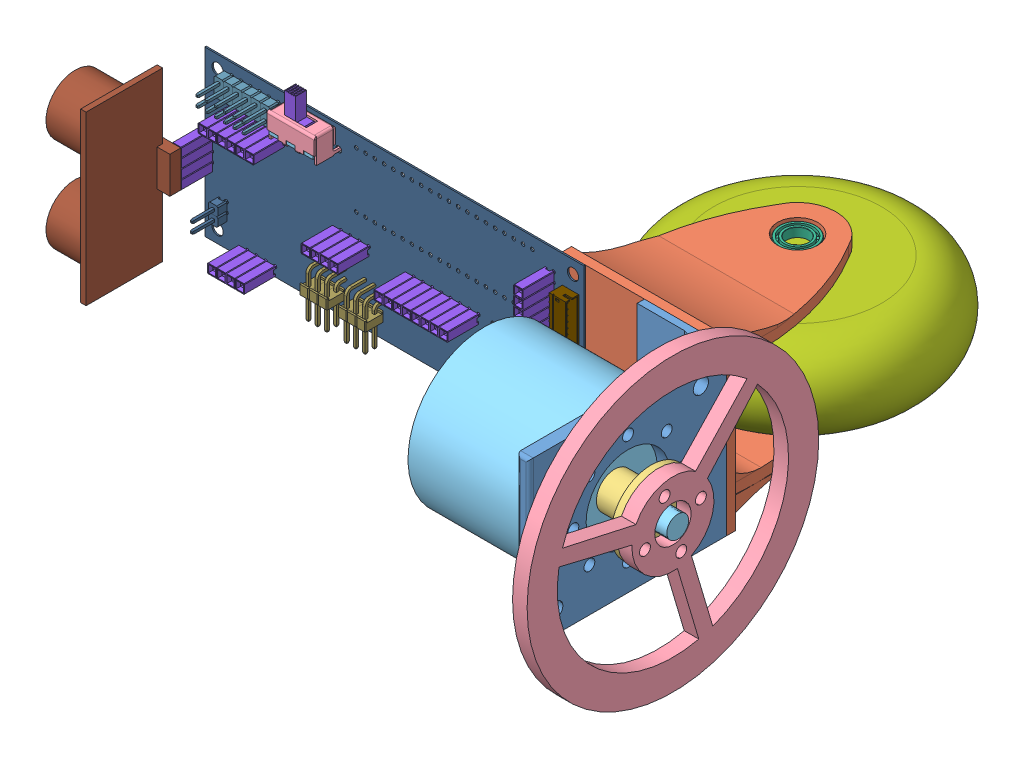
SolidWorks assembly 自行车-装配体_1, configuration Default. Lengths in mm.
Overall size (170.21 99.47 153.76).
186 component instances, 29 part files, 0 mates.
Components (placement in the parent):
- 自行车-装配体-1: 自行车-装配体 [默认] at (98.9927 99.8589 184.7808) size (170.21 99.47 153.76)
  - 自行车-飞轮电机固定件-1: 自行车-飞轮电机固定件 [默认] at (13.6732 19.776 -50.6548) size (22.5 45 54)
  - 自行车-车轮后叉件-1: 自行车-车轮后叉件 [默认] at (36.1732 19.776 -50.6548) x (0 -1 0) z (0 0 -1) size (45 45 52.5)
  - 自行车-6mm联轴器模型-1: 自行车-6mm联轴器模型 [默认] at (44.4868 -2.724 -23.6548) x (0 -0.004012 0.999992) z (-1 0 0) size (22 22 12)
  - 自行车-80mm飞轮模型-1: 自行车-80mm飞轮模型 [默认] at (48.4868 -2.724 -23.6548) x (0 0.958573 0.284848) z (-1 0 0) size (80 80 4)
  - 自行车-飞轮电机模型-1: 自行车-飞轮电机模型 [默认] at (-3.1856 -2.724 -23.6548) x (0 0.181181 -0.98345) z (1 0 0) size (42 42 53)
  - miniature radial ball bearings gb-2: miniature radial ball bearings gb [Rolling bearings FF617-6  GB 7218-1995] at (13.6732 -17.974 -92.6548) x (0 1 0) z (-0.404168 0 0.914685) size (2.5 11.2 11.2)
  - miniature radial ball bearings gb-5: miniature radial ball bearings gb [Rolling bearings FF617-6  GB 7218-1995] at (13.6732 12.526 -92.6548) x (0 -1 0) z (0.445436 0 0.895314) size (2.5 11.2 11.2)
  - 自行车-轮子模型-1: 自行车-轮子模型 [默认] at (0.6732 -2.7471 -92.6468) x (1 0 -0.000617) z (0.000617 0 1) size (70 24 70)
  - balance_bike20211103.step-2: balance_bike20211103.step [默认] at (-167.5194 -100.224 -49.0548) size (104.02 52.12 11.85)
    - Bluetooth.step-1: Bluetooth.step [默认] at origin size (2.54 15.24 11.5)
      - HDR2.54-1P_M.step-1: HDR2.54-1P_M.step [默认] at (156.6926 106.8324 0) x (0 -1 0) z (0 0 1) size (2.54 2.54 11.5)
        - HDR2.54-1P_M-0.step-1: HDR2.54-1P_M-0.step [默认] at origin size (2.54 2.54 11.5)
        - LOGO__.step-1: LOGO__.step [默认] at (0 0.9721 0.0285) x (-1 0 0) z (0 0 -1) size (0.45 0.52 0)
      - HDR2.54-1P_M.step-2: HDR2.54-1P_M.step [默认] at (156.6926 101.7524 0) x (0 -1 0) z (0 0 1) size (2.54 2.54 11.5)
        - HDR2.54-1P_M-0.step-1: HDR2.54-1P_M-0.step [默认] at origin size (2.54 2.54 11.5)
        - LOGO__.step-1: LOGO__.step [默认] at (0 0.9721 0.0285) x (-1 0 0) z (0 0 -1) size (0.45 0.52 0)
      - HDR2.54-1P_M.step-3: HDR2.54-1P_M.step [默认] at (156.6926 104.2924 0) x (0 -1 0) z (0 0 1) size (2.54 2.54 11.5)
        - HDR2.54-1P_M-0.step-1: HDR2.54-1P_M-0.step [默认] at origin size (2.54 2.54 11.5)
        - LOGO__.step-1: LOGO__.step [默认] at (0 0.9721 0.0285) x (-1 0 0) z (0 0 -1) size (0.45 0.52 0)
      - HDR2.54-1P_M.step-4: HDR2.54-1P_M.step [默认] at (156.6926 114.4524 0) x (0 -1 0) z (0 0 1) size (2.54 2.54 11.5)
        - HDR2.54-1P_M-0.step-1: HDR2.54-1P_M-0.step [默认] at origin size (2.54 2.54 11.5)
        - LOGO__.step-1: LOGO__.step [默认] at (0 0.9721 0.0285) x (-1 0 0) z (0 0 -1) size (0.45 0.52 0)
      - HDR2.54-1P_M.step-5: HDR2.54-1P_M.step [默认] at (156.6926 109.3724 0) x (0 -1 0) z (0 0 1) size (2.54 2.54 11.5)
        - HDR2.54-1P_M-0.step-1: HDR2.54-1P_M-0.step [默认] at origin size (2.54 2.54 11.5)
        - LOGO__.step-1: LOGO__.step [默认] at (0 0.9721 0.0285) x (-1 0 0) z (0 0 -1) size (0.45 0.52 0)
      - HDR2.54-1P_M.step-6: HDR2.54-1P_M.step [默认] at (156.6926 111.9124 0) x (0 -1 0) z (0 0 1) size (2.54 2.54 11.5)
        - HDR2.54-1P_M-0.step-1: HDR2.54-1P_M-0.step [默认] at origin size (2.54 2.54 11.5)
        - LOGO__.step-1: LOGO__.step [默认] at (0 0.9721 0.0285) x (-1 0 0) z (0 0 -1) size (0.45 0.52 0)
    - JP1.step-1: JP1.step [默认] at origin size (2.54 5.08 11.5)
      - HDR2.54-1P.step-1: HDR2.54-1P.step [默认] at (67 83.73 0) x (1 0 0) z (0 0 1) size (2.54 2.54 11.5)
        - HDR2.54-1P-1.step-1: HDR2.54-1P-1.step [默认] at origin size (2.54 2.54 11.5)
        - LOGO__-2.step-1: LOGO__-2.step [默认] at (-0.9958 0 0.0285) x (0 -1 0) z (0 0 -1) size (0.45 0.52 0)
      - HDR2.54-1P.step-2: HDR2.54-1P.step [默认] at (67 86.27 0) x (1 0 0) z (0 0 1) size (2.54 2.54 11.5)
        - HDR2.54-1P-1.step-1: HDR2.54-1P-1.step [默认] at origin size (2.54 2.54 11.5)
        - LOGO__-2.step-1: LOGO__-2.step [默认] at (-0.9958 0 0.0285) x (0 -1 0) z (0 0 -1) size (0.45 0.52 0)
    - JP2.step-1: JP2.step [默认] at origin size (7.62 12.85 8.1)
      - HDR-1x2_H.step-1: HDR-1x2_H.step [默认] at (107.4928 86.741 0) size (2.54 12.85 8.1)
        - HDR-1x2_H-3.step-1: HDR-1x2_H-3.step [默认] at origin size (2.54 12.85 8.1)
        - LOGO__-4.step-1: LOGO__-4.step [默认] at (0 -4.7829 0.017) x (-1 0 0) z (0 0 -1) size (0.9 1.04 0.01)
      - HDR-1x2_H.step-2: HDR-1x2_H.step [默认] at (104.9528 86.741 0) size (2.54 12.85 8.1)
        - HDR-1x2_H-3.step-1: HDR-1x2_H-3.step [默认] at origin size (2.54 12.85 8.1)
        - LOGO__-4.step-1: LOGO__-4.step [默认] at (0 -4.7829 0.017) x (-1 0 0) z (0 0 -1) size (0.9 1.04 0.01)
      - HDR-1x2_H.step-3: HDR-1x2_H.step [默认] at (110.0328 86.741 0) size (2.54 12.85 8.1)
        - HDR-1x2_H-3.step-1: HDR-1x2_H-3.step [默认] at origin size (2.54 12.85 8.1)
        - LOGO__-4.step-1: LOGO__-4.step [默认] at (0 -4.7829 0.017) x (-1 0 0) z (0 0 -1) size (0.9 1.04 0.01)
    - JP3.step-1: JP3.step [默认] at origin size (7.62 12.85 8.1)
      - HDR-1x2_H.step-1: HDR-1x2_H.step [默认] at (97.0026 86.741 0) x (1 0 0) z (0 0 1) size (2.54 12.85 8.1)
        - HDR-1x2_H-3.step-1: HDR-1x2_H-3.step [默认] at origin size (2.54 12.85 8.1)
        - LOGO__-4.step-1: LOGO__-4.step [默认] at (0 -4.7829 0.017) x (-1 0 0) z (0 0 -1) size (0.9 1.04 0.01)
      - HDR-1x2_H.step-2: HDR-1x2_H.step [默认] at (94.4626 86.741 0) x (1 0 0) z (0 0 1) size (2.54 12.85 8.1)
        - HDR-1x2_H-3.step-1: HDR-1x2_H-3.step [默认] at origin size (2.54 12.85 8.1)
        - LOGO__-4.step-1: LOGO__-4.step [默认] at (0 -4.7829 0.017) x (-1 0 0) z (0 0 -1) size (0.9 1.04 0.01)
      - HDR-1x2_H.step-3: HDR-1x2_H.step [默认] at (99.5426 86.741 0) x (1 0 0) z (0 0 1) size (2.54 12.85 8.1)
        - HDR-1x2_H-3.step-1: HDR-1x2_H-3.step [默认] at origin size (2.54 12.85 8.1)
        - LOGO__-4.step-1: LOGO__-4.step [默认] at (0 -4.7829 0.017) x (-1 0 0) z (0 0 -1) size (0.9 1.04 0.01)
    - JP4.step-1: JP4.step [默认] at origin size (15.24 5.08 11.5)
      - HDR2.54-1x2P.step-1: HDR2.54-1x2P.step [默认] at (68.5038 116.9416 0) x (1 0 0) z (0 0 1) size (2.54 5.08 11.5)
        - HDR2.54-1x2P-5.step-1: HDR2.54-1x2P-5.step [默认] at origin size (2.54 5.08 11.5)
        - LOGO__-6.step-1: LOGO__-6.step [默认] at (0 -1.2605 0.4975) x (-1 0 0) z (0 0 -1) size (0.75 0.87 0.01)
      - HDR2.54-1x2P.step-2: HDR2.54-1x2P.step [默认] at (76.1238 116.9416 0) x (1 0 0) z (0 0 1) size (2.54 5.08 11.5)
        - HDR2.54-1x2P-5.step-1: HDR2.54-1x2P-5.step [默认] at origin size (2.54 5.08 11.5)
        - LOGO__-6.step-1: LOGO__-6.step [默认] at (0 -1.2605 0.4975) x (-1 0 0) z (0 0 -1) size (0.75 0.87 0.01)
      - HDR2.54-1x2P.step-3: HDR2.54-1x2P.step [默认] at (73.5838 116.9416 0) x (1 0 0) z (0 0 1) size (2.54 5.08 11.5)
        - HDR2.54-1x2P-5.step-1: HDR2.54-1x2P-5.step [默认] at origin size (2.54 5.08 11.5)
        - LOGO__-6.step-1: LOGO__-6.step [默认] at (0 -1.2605 0.4975) x (-1 0 0) z (0 0 -1) size (0.75 0.87 0.01)
      - HDR2.54-1x2P.step-4: HDR2.54-1x2P.step [默认] at (81.2038 116.9416 0) x (1 0 0) z (0 0 1) size (2.54 5.08 11.5)
        - HDR2.54-1x2P-5.step-1: HDR2.54-1x2P-5.step [默认] at origin size (2.54 5.08 11.5)
        - LOGO__-6.step-1: LOGO__-6.step [默认] at (0 -1.2605 0.4975) x (-1 0 0) z (0 0 -1) size (0.75 0.87 0.01)
      - HDR2.54-1x2P.step-5: HDR2.54-1x2P.step [默认] at (78.6638 116.9416 0) x (1 0 0) z (0 0 1) size (2.54 5.08 11.5)
        - HDR2.54-1x2P-5.step-1: HDR2.54-1x2P-5.step [默认] at origin size (2.54 5.08 11.5)
        - LOGO__-6.step-1: LOGO__-6.step [默认] at (0 -1.2605 0.4975) x (-1 0 0) z (0 0 -1) size (0.75 0.87 0.01)
      - HDR2.54-1x2P.step-6: HDR2.54-1x2P.step [默认] at (71.0438 116.9416 0) x (1 0 0) z (0 0 1) size (2.54 5.08 11.5)
        - HDR2.54-1x2P-5.step-1: HDR2.54-1x2P-5.step [默认] at origin size (2.54 5.08 11.5)
        - LOGO__-6.step-1: LOGO__-6.step [默认] at (0 -1.2605 0.4975) x (-1 0 0) z (0 0 -1) size (0.75 0.87 0.01)
    - JP6.step-1: JP6.step [默认] at origin size (5 13.5 6)
      - ZH1.5-WI-8P.step-1: ZH1.5-WI-8P.step [默认] at (160.0708 106.9594 0) x (0 1 0) z (0 0 1) size (13.5 5 6)
        - ZH1.5-WI-____.step-1: ZH1.5-WI-____.step [默认] at (-5.25 0 0.05) size (0.5 4 4.75)
        - ZH1.5-WI-____.step-2: ZH1.5-WI-____.step [默认] at (-3.75 0 0.05) size (0.5 4 4.75)
        - ZH1.5-WI-____.step-3: ZH1.5-WI-____.step [默认] at (-2.25 0 0.05) size (0.5 4 4.75)
        - ZH1.5-WI-____.step-4: ZH1.5-WI-____.step [默认] at (-0.75 0 0.05) size (0.5 4 4.75)
        - LOGO__0.25.step-1: LOGO__0.25.step [默认] at (-0.0154 -2.5616 0.045) size (0.75 0.87 0.01)
        - ZH1.5-WI-____.step-5: ZH1.5-WI-____.step [默认] at (0.75 0 0.05) size (0.5 4 4.75)
        - ZH1.5-WI-____.step-6: ZH1.5-WI-____.step [默认] at (2.25 0 0.05) size (0.5 4 4.75)
        - ZH1.5-WI-____.step-7: ZH1.5-WI-____.step [默认] at (3.75 0 0.05) size (0.5 4 4.75)
        - ZH1.5-WI-____.step-8: ZH1.5-WI-____.step [默认] at (5.25 0 0.05) size (0.5 4 4.75)
        - ZH1.5-WI-8P-7.step-1: ZH1.5-WI-8P-7.step [默认] at origin size (13.5 4.5 3.6)
    - MOTOR1.step-1: MOTOR1.step [默认] at origin size (6.6 5.9 7.4)
      - PH2.0-WI-2P.step-1: PH2.0-WI-2P.step [默认] at (158.7246 86.868 0) x (0 1 0) z (0 0 1) size (5.9 6.6 7.4)
        - PH2.0-WI-2P-8.step-1: PH2.0-WI-2P-8.step [默认] at origin size (5.9 6 4.7)
        - PH2.0-WI-____.step-1: PH2.0-WI-____.step [默认] at (-1 0 0.05) size (0.6 5.5 6)
        - PH2.0-WI-____.step-2: PH2.0-WI-____.step [默认] at (1 0 0.05) size (0.6 5.5 6)
        - LOGO__0.25-9.step-1: LOGO__0.25-9.step [默认] at (-0.0263 -2.2762 0.045) size (0.75 0.87 0.01)
    - MPU6050.step-1: MPU6050.step [默认] at origin size (20.32 2.54 11.5)
      - HDR2.54-1P_M.step-1: HDR2.54-1P_M.step [默认] at (120.8532 94.0308 0) x (1 0 0) z (0 0 1) size (2.54 2.54 11.5)
        - HDR2.54-1P_M-0.step-1: HDR2.54-1P_M-0.step [默认] at origin size (2.54 2.54 11.5)
        - LOGO__.step-1: LOGO__.step [默认] at (0 0.9721 0.0285) x (-1 0 0) z (0 0 -1) size (0.45 0.52 0)
      - HDR2.54-1P_M.step-2: HDR2.54-1P_M.step [默认] at (125.9332 94.0308 0) x (1 0 0) z (0 0 1) size (2.54 2.54 11.5)
        - HDR2.54-1P_M-0.step-1: HDR2.54-1P_M-0.step [默认] at origin size (2.54 2.54 11.5)
        - LOGO__.step-1: LOGO__.step [默认] at (0 0.9721 0.0285) x (-1 0 0) z (0 0 -1) size (0.45 0.52 0)
      - HDR2.54-1P_M.step-3: HDR2.54-1P_M.step [默认] at (128.4732 94.0308 0) x (1 0 0) z (0 0 1) size (2.54 2.54 11.5)
        - HDR2.54-1P_M-0.step-1: HDR2.54-1P_M-0.step [默认] at origin size (2.54 2.54 11.5)
        - LOGO__.step-1: LOGO__.step [默认] at (0 0.9721 0.0285) x (-1 0 0) z (0 0 -1) size (0.45 0.52 0)
      - HDR2.54-1P_M.step-4: HDR2.54-1P_M.step [默认] at (123.3932 94.0308 0) x (1 0 0) z (0 0 1) size (2.54 2.54 11.5)
        - HDR2.54-1P_M-0.step-1: HDR2.54-1P_M-0.step [默认] at origin size (2.54 2.54 11.5)
        - LOGO__.step-1: LOGO__.step [默认] at (0 0.9721 0.0285) x (-1 0 0) z (0 0 -1) size (0.45 0.52 0)
      - HDR2.54-1P_M.step-5: HDR2.54-1P_M.step [默认] at (133.5532 94.0308 0) x (1 0 0) z (0 0 1) size (2.54 2.54 11.5)
        - HDR2.54-1P_M-0.step-1: HDR2.54-1P_M-0.step [默认] at origin size (2.54 2.54 11.5)
        - LOGO__.step-1: LOGO__.step [默认] at (0 0.9721 0.0285) x (-1 0 0) z (0 0 -1) size (0.45 0.52 0)
      - HDR2.54-1P_M.step-6: HDR2.54-1P_M.step [默认] at (136.0932 94.0308 0) x (1 0 0) z (0 0 1) size (2.54 2.54 11.5)
        - HDR2.54-1P_M-0.step-1: HDR2.54-1P_M-0.step [默认] at origin size (2.54 2.54 11.5)
        - LOGO__.step-1: LOGO__.step [默认] at (0 0.9721 0.0285) x (-1 0 0) z (0 0 -1) size (0.45 0.52 0)
      - HDR2.54-1P_M.step-7: HDR2.54-1P_M.step [默认] at (131.0132 94.0308 0) x (1 0 0) z (0 0 1) size (2.54 2.54 11.5)
        - HDR2.54-1P_M-0.step-1: HDR2.54-1P_M-0.step [默认] at origin size (2.54 2.54 11.5)
        - LOGO__.step-1: LOGO__.step [默认] at (0 0.9721 0.0285) x (-1 0 0) z (0 0 -1) size (0.45 0.52 0)
      - HDR2.54-1P_M.step-8: HDR2.54-1P_M.step [默认] at (118.3132 94.0308 0) x (1 0 0) z (0 0 1) size (2.54 2.54 11.5)
        - HDR2.54-1P_M-0.step-1: HDR2.54-1P_M-0.step [默认] at origin size (2.54 2.54 11.5)
        - LOGO__.step-1: LOGO__.step [默认] at (0 0.9721 0.0285) x (-1 0 0) z (0 0 -1) size (0.45 0.52 0)
    - S1.step-1: S1.step [默认] at origin size (13 12.9 9.1)
      - User_Library-SLIDE_SWITCH_SS12F23.step-1: User_Library-SLIDE_SWITCH_SS12F23.step [默认] at (91.2963 119.8635 0.5) x (-1 0 0) z (0 1 0) size (13 9.1 12.9)
        - User_Library-SLIDE_SWITCH_SS12F23_SLIDE_SWITCH_SS12F23_CAPA_Valor_predeterminado.step-1: User_Library-SLIDE_SWITCH_SS12F23_SLIDE_SWITCH_SS12F23_CAPA_Valor_predeterminado.step [默认] at (-0.1668 2.3476 0) size (13 8.18 6.9)
        - User_Library-SLIDE_SWITCH_SS12F23_SLIDE_SWITCH_SS12F23_PCB_Valor_predeterminado.step-1: User_Library-SLIDE_SWITCH_SS12F23_SLIDE_SWITCH_SS12F23_PCB_Valor_predeterminado.step [默认] at (12.2412 -9.4974 -5) size (12 5.5 1)
        - User_Library-SLIDE_SWITCH_SS12F23_SLIDE_SWITCH_SS12F23_CENTRAL_Valor_predeterminado.step-1: User_Library-SLIDE_SWITCH_SS12F23_SLIDE_SWITCH_SS12F23_CENTRAL_Valor_predeterminado.step [默认] at (-1.4168 2.5976 -3) size (2.5 6.45 3.5)
        - User_Library-SLIDE_SWITCH_SS12F23_SLIDE_SWITCH_SS12F23_LATERAL_Valor_predeterminado.step-1: User_Library-SLIDE_SWITCH_SS12F23_SLIDE_SWITCH_SS12F23_LATERAL_Valor_predeterminado.step [默认] at (-4.4168 2.5976 -3) size (2.5 6.45 3)
        - User_Library-SLIDE_SWITCH_SS12F23_SLIDE_SWITCH_SS12F23_LATERAL_Valor_predeterminado.step-2: User_Library-SLIDE_SWITCH_SS12F23_SLIDE_SWITCH_SS12F23_LATERAL_Valor_predeterminado.step [默认] at (1.5832 2.5976 -3) size (2.5 6.45 3)
        - User_Library-SLIDE_SWITCH_SS12F23_SLIDE_SWITCH_SS12F23_ATUADOR_Valor_predeterminado.step-1: User_Library-SLIDE_SWITCH_SS12F23_SLIDE_SWITCH_SS12F23_ATUADOR_Valor_predeterminado.step [默认] at (1.3332 2.3976 -3.25) size (7 4.5 9.75)
        - User_Library-SLIDE_SWITCH_SS12F23_SLIDE_SWITCH_SS12F23_Contato_Valor_predeterminado.step-1: User_Library-SLIDE_SWITCH_SS12F23_SLIDE_SWITCH_SS12F23_Contato_Valor_predeterminado.step [默认] at (3.3332 3.1476 -2.25) x (0 -1 0) z (0 0 -1) size (1.5 5 2)
    - U1.step-1: U1.step [默认] at origin size (15.24 34.54 11.5)
      - HDR2.54-1P_M.step-1: HDR2.54-1P_M.step [默认] at (75.2254 77.5402 0) x (-1 0 0) z (0 0 1) size (2.54 2.54 11.5)
        - HDR2.54-1P_M-0.step-1: HDR2.54-1P_M-0.step [默认] at origin size (2.54 2.54 11.5)
        - LOGO__.step-1: LOGO__.step [默认] at (0 0.9721 0.0285) x (-1 0 0) z (0 0 -1) size (0.45 0.52 0)
      - HDR2.54-1P_M.step-2: HDR2.54-1P_M.step [默认] at (72.6854 77.5402 0) x (-1 0 0) z (0 0 1) size (2.54 2.54 11.5)
        - HDR2.54-1P_M-0.step-1: HDR2.54-1P_M-0.step [默认] at origin size (2.54 2.54 11.5)
        - LOGO__.step-1: LOGO__.step [默认] at (0 0.9721 0.0285) x (-1 0 0) z (0 0 -1) size (0.45 0.52 0)
      - HDR2.54-1P_M.step-3: HDR2.54-1P_M.step [默认] at (80.3054 77.5402 0) x (-1 0 0) z (0 0 1) size (2.54 2.54 11.5)
        - HDR2.54-1P_M-0.step-1: HDR2.54-1P_M-0.step [默认] at origin size (2.54 2.54 11.5)
        - LOGO__.step-1: LOGO__.step [默认] at (0 0.9721 0.0285) x (-1 0 0) z (0 0 -1) size (0.45 0.52 0)
      - HDR2.54-1P_M.step-4: HDR2.54-1P_M.step [默认] at (77.7654 77.5402 0) x (-1 0 0) z (0 0 1) size (2.54 2.54 11.5)
        - HDR2.54-1P_M-0.step-1: HDR2.54-1P_M-0.step [默认] at origin size (2.54 2.54 11.5)
        - LOGO__.step-1: LOGO__.step [默认] at (0 0.9721 0.0285) x (-1 0 0) z (0 0 -1) size (0.45 0.52 0)
      - HDR2.54-1P_M.step-5: HDR2.54-1P_M.step [默认] at (75.2255 109.5403 0) x (-1 0 0) z (0 0 1) size (2.54 2.54 11.5)
        - HDR2.54-1P_M-0.step-1: HDR2.54-1P_M-0.step [默认] at origin size (2.54 2.54 11.5)
        - LOGO__.step-1: LOGO__.step [默认] at (0 0.9721 0.0285) x (-1 0 0) z (0 0 -1) size (0.45 0.52 0)
      - HDR2.54-1P_M.step-6: HDR2.54-1P_M.step [默认] at (70.1455 109.5403 0) x (-1 0 0) z (0 0 1) size (2.54 2.54 11.5)
        - HDR2.54-1P_M-0.step-1: HDR2.54-1P_M-0.step [默认] at origin size (2.54 2.54 11.5)
        - LOGO__.step-1: LOGO__.step [默认] at (0 0.9721 0.0285) x (-1 0 0) z (0 0 -1) size (0.45 0.52 0)
      - HDR2.54-1P_M.step-7: HDR2.54-1P_M.step [默认] at (72.6855 109.5403 0) x (-1 0 0) z (0 0 1) size (2.54 2.54 11.5)
        - HDR2.54-1P_M-0.step-1: HDR2.54-1P_M-0.step [默认] at origin size (2.54 2.54 11.5)
        - LOGO__.step-1: LOGO__.step [默认] at (0 0.9721 0.0285) x (-1 0 0) z (0 0 -1) size (0.45 0.52 0)
      - HDR2.54-1P_M.step-8: HDR2.54-1P_M.step [默认] at (82.8455 109.5403 0) x (-1 0 0) z (0 0 1) size (2.54 2.54 11.5)
        - HDR2.54-1P_M-0.step-1: HDR2.54-1P_M-0.step [默认] at origin size (2.54 2.54 11.5)
        - LOGO__.step-1: LOGO__.step [默认] at (0 0.9721 0.0285) x (-1 0 0) z (0 0 -1) size (0.45 0.52 0)
      - HDR2.54-1P_M.step-9: HDR2.54-1P_M.step [默认] at (77.7655 109.5403 0) x (-1 0 0) z (0 0 1) size (2.54 2.54 11.5)
        - HDR2.54-1P_M-0.step-1: HDR2.54-1P_M-0.step [默认] at origin size (2.54 2.54 11.5)
        - LOGO__.step-1: LOGO__.step [默认] at (0 0.9721 0.0285) x (-1 0 0) z (0 0 -1) size (0.45 0.52 0)
      - HDR2.54-1P_M.step-10: HDR2.54-1P_M.step [默认] at (80.3055 109.5403 0) x (-1 0 0) z (0 0 1) size (2.54 2.54 11.5)
        - HDR2.54-1P_M-0.step-1: HDR2.54-1P_M-0.step [默认] at origin size (2.54 2.54 11.5)
        - LOGO__.step-1: LOGO__.step [默认] at (0 0.9721 0.0285) x (-1 0 0) z (0 0 -1) size (0.45 0.52 0)
    - ultrasonic.step-1: ultrasonic.step [默认] at origin size (2.54 10.16 11.5)
      - HDR2.54-1P_M.step-1: HDR2.54-1P_M.step [默认] at (63 96.23 0) x (0 -1 0) z (0 0 1) size (2.54 2.54 11.5)
        - HDR2.54-1P_M-0.step-1: HDR2.54-1P_M-0.step [默认] at origin size (2.54 2.54 11.5)
        - LOGO__.step-1: LOGO__.step [默认] at (0 0.9721 0.0285) x (-1 0 0) z (0 0 -1) size (0.45 0.52 0)
      - HDR2.54-1P_M.step-2: HDR2.54-1P_M.step [默认] at (63 93.69 0) x (0 -1 0) z (0 0 1) size (2.54 2.54 11.5)
        - HDR2.54-1P_M-0.step-1: HDR2.54-1P_M-0.step [默认] at origin size (2.54 2.54 11.5)
        - LOGO__.step-1: LOGO__.step [默认] at (0 0.9721 0.0285) x (-1 0 0) z (0 0 -1) size (0.45 0.52 0)
      - HDR2.54-1P_M.step-3: HDR2.54-1P_M.step [默认] at (63 101.31 0) x (0 -1 0) z (0 0 1) size (2.54 2.54 11.5)
        - HDR2.54-1P_M-0.step-1: HDR2.54-1P_M-0.step [默认] at origin size (2.54 2.54 11.5)
        - LOGO__.step-1: LOGO__.step [默认] at (0 0.9721 0.0285) x (-1 0 0) z (0 0 -1) size (0.45 0.52 0)
      - HDR2.54-1P_M.step-4: HDR2.54-1P_M.step [默认] at (63 98.77 0) x (0 -1 0) z (0 0 1) size (2.54 2.54 11.5)
        - HDR2.54-1P_M-0.step-1: HDR2.54-1P_M-0.step [默认] at origin size (2.54 2.54 11.5)
        - LOGO__.step-1: LOGO__.step [默认] at (0 0.9721 0.0285) x (-1 0 0) z (0 0 -1) size (0.45 0.52 0)
    - OLED.step-1: OLED.step [默认] at origin size (10.16 2.54 11.5)
      - HDR2.54-1P_M.step-1: HDR2.54-1P_M.step [默认] at (103.4486 95.1112 0) x (-1 0 0) z (0 0 1) size (2.54 2.54 11.5)
        - HDR2.54-1P_M-0.step-1: HDR2.54-1P_M-0.step [默认] at origin size (2.54 2.54 11.5)
        - LOGO__.step-1: LOGO__.step [默认] at (0 0.9721 0.0285) x (-1 0 0) z (0 0 -1) size (0.45 0.52 0)
      - HDR2.54-1P_M.step-2: HDR2.54-1P_M.step [默认] at (105.9886 95.1112 0) x (-1 0 0) z (0 0 1) size (2.54 2.54 11.5)
        - HDR2.54-1P_M-0.step-1: HDR2.54-1P_M-0.step [默认] at origin size (2.54 2.54 11.5)
        - LOGO__.step-1: LOGO__.step [默认] at (0 0.9721 0.0285) x (-1 0 0) z (0 0 -1) size (0.45 0.52 0)
      - HDR2.54-1P_M.step-3: HDR2.54-1P_M.step [默认] at (98.3686 95.1112 0) x (-1 0 0) z (0 0 1) size (2.54 2.54 11.5)
        - HDR2.54-1P_M-0.step-1: HDR2.54-1P_M-0.step [默认] at origin size (2.54 2.54 11.5)
        - LOGO__.step-1: LOGO__.step [默认] at (0 0.9721 0.0285) x (-1 0 0) z (0 0 -1) size (0.45 0.52 0)
      - HDR2.54-1P_M.step-4: HDR2.54-1P_M.step [默认] at (100.9086 95.1112 0) x (-1 0 0) z (0 0 1) size (2.54 2.54 11.5)
        - HDR2.54-1P_M-0.step-1: HDR2.54-1P_M-0.step [默认] at origin size (2.54 2.54 11.5)
        - LOGO__.step-1: LOGO__.step [默认] at (0 0.9721 0.0285) x (-1 0 0) z (0 0 -1) size (0.45 0.52 0)
    - Board.step-1: Board.step [默认] at (0 0 -1.6) size (104 45 0.41)
  - 自行车-超声波模型-1: 自行车-超声波模型 [默认] at (-106.8994 20.196 -18.0604) x (0 -1 0) z (-1 0 0) size (46 22.52 17)
